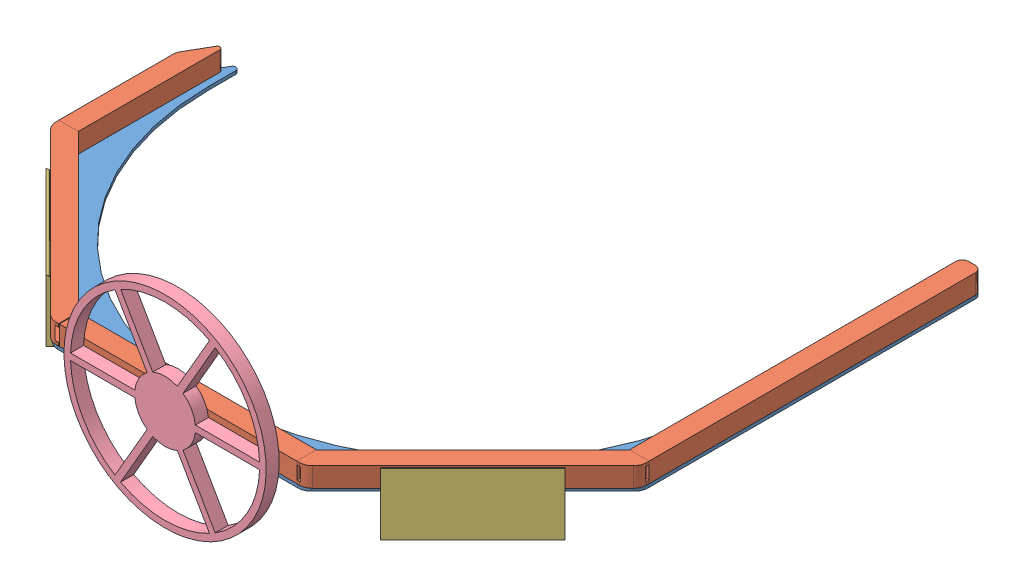
SolidWorks assembly recycling_rotate_weldment, configuration Default. Lengths in mm.
Overall size (582.57 228.04 508).
9 component instances, 4 part files, 24 mates.
Components (placement in the parent):
- recycling_rotate_plate-1: recycling_rotate_plate [Default] at origin size (574.68 3.17 495.3)
- recycling_rotate_tube-16: recycling_rotate_tube [-2] at (-115.2525 12.7 282.575) x (0 0 -1) z (1 0 0) size (19.05 19.05 231.14)
- recycling_rotate_tube-1: recycling_rotate_tube [Default] at (277.8125 12.7 120.65) x (-1 0 0) z (0 0 -1) size (19.05 19.05 323.85)
- recycling_rotate_tube-14: recycling_rotate_tube [-3] at (-277.8125 12.7 -463.55) size (19.05 19.05 140.36)
- recycling_rotate_tube-17: recycling_rotate_tube [-4] at (14.5071 12.7 387.9008) x (-0.707107 0 -0.707107) z (0.707107 0 -0.707107) size (19.05 19.05 242.47)
- recycling_rotate_tube-18: recycling_rotate_tube [-4] at (-14.5071 12.7 387.9008) x (0.707107 0 -0.707107) z (-0.707107 0 -0.707107) size (19.05 19.05 242.47)
- recycling_rotate_l-angle-1: recycling_rotate_l-angle [PreviewCfg] at (207.8029 -38.1 212.5654) x (-0.707107 0 -0.707107) z (0.707107 0 -0.707107) size (34.92 60.32 127)
- recycling_rotate_l-angle-2: recycling_rotate_l-angle [PreviewCfg] at (-207.8029 -38.1 212.5654) x (0.707107 0 -0.707107) z (0.707107 0 0.707107) size (34.92 60.32 127)
- recycling_rotate_wheel-1: recycling_rotate_wheel [Default] at (0.3175 12.7 292.1) x (0.984808 0.173648 0) z (0.173648 -0.984808 0) size (196.85 12.7 196.85)
Mates (geometry in assembly coordinates):
- Coincident1: coincident anti-aligned: plane of recycling_rotate_plate-1 through (0 3.175 0) normal (0 1 0); plane of recycling_rotate_tube-1 through (268.2875 3.175 -203.2) normal (0 -1 0)
- Coincident3: coincident aligned: plane of recycling_rotate_plate-1 through (287.3375 3.175 292.1) normal (1 0 0); plane of recycling_rotate_tube-1 through (287.3375 3.175 -203.2) normal (1 0 0)
- Coincident4: coincident anti-aligned: plane of recycling_rotate_plate-1 through (0 3.175 0) normal (0 1 0); plane of recycling_rotate_tube-14 through (-268.2875 3.175 120.65) normal (0 -1 0)
- Coincident6: coincident aligned: plane of recycling_rotate_plate-1 through (-287.3375 3.175 5.8941) normal (-1 0 0); plane of recycling_rotate_tube-14 through (-287.3375 3.175 120.65) normal (-1 0 0)
- Coincident7: coincident anti-aligned: plane of recycling_rotate_plate-1 through (0 3.175 0) normal (0 1 0); plane of recycling_rotate_tube-16 through (115.8875 3.175 273.05) normal (0 -1 0)
- Coincident13: coincident aligned: plane of recycling_rotate_plate-1 through (287.3375 3.175 292.1) normal (0 0 1); plane of recycling_rotate_tube-16 through (115.8875 3.175 292.1) normal (0 0 1)
- Coincident29: coincident anti-aligned: plane of recycling_rotate_plate-1 through (0 3.175 0) normal (0 1 0); plane of recycling_rotate_tube-17 through (414.1285 3.175 -25.191) normal (0 -1 0)
- Coincident33: coincident aligned: plane of recycling_rotate_tube-1 through (287.3375 3.175 -203.2) normal (1 0 0); plane of recycling_rotate_tube-17 through (287.3375 3.175 128.5408) normal (1 0 0)
- Coincident34: coincident aligned: plane of recycling_rotate_tube-16 through (115.8875 3.175 292.1) normal (0 0 1); plane of recycling_rotate_tube-17 through (123.7783 3.175 292.1) normal (0 0 1)
- Coincident35: coincident anti-aligned: plane of recycling_rotate_plate-1 through (0 3.175 0) normal (0 1 0); plane of recycling_rotate_tube-18 through (-414.1285 3.175 -25.191) normal (0 -1 0)
- Coincident36: coincident aligned: plane of recycling_rotate_tube-14 through (-287.3375 3.175 120.65) normal (-1 0 0); plane of recycling_rotate_tube-18 through (-287.3375 22.225 128.5408) normal (-1 0 0)
- Coincident37: coincident aligned: plane of recycling_rotate_tube-16 through (115.8875 3.175 292.1) normal (0 0 1); plane of recycling_rotate_tube-18 through (-123.7783 22.225 292.1) normal (0 0 1)
- Coincident38: coincident anti-aligned: plane of recycling_rotate_tube-1 through (277.8125 12.7 120.65) normal (0 0 1); plane of recycling_rotate_tube-17 through (14.5071 3.175 120.65) normal (0 0 -1)
- Coincident39: coincident anti-aligned: plane of recycling_rotate_tube-14 through (-277.8125 12.7 120.65) normal (0 0 1); plane of recycling_rotate_tube-18 through (-14.5071 22.225 120.65) normal (0 0 -1)
- Coincident40: coincident anti-aligned: plane of recycling_rotate_tube-16 through (115.8875 12.7 282.575) normal (1 0 0); plane of recycling_rotate_tube-17 through (115.8875 3.175 299.9908) normal (-1 0 0)
- Coincident41: coincident anti-aligned: plane of recycling_rotate_tube-17 through (427.5989 3.175 -11.7206) normal (0.707107 0 0.707107); plane of recycling_rotate_l-angle-1 through (250.4592 19.0551 165.4191) normal (-0.707107 0 -0.707107)
- Coincident42: coincident: plane of recycling_rotate_tube-17 through (414.1285 22.225 -25.191) normal (0 1 0); line of recycling_rotate_l-angle-1 through (252.7042 22.225 167.6642) axis (-0.707107 0 0.707107)
- Coincident43: coincident aligned: plane of recycling_rotate_l-angle-1 through (207.8029 -38.1 212.5654) normal (0.707107 0 -0.707107); plane of recycling_rotate_tube-17 through (198.8227 12.7 203.5852) normal (0.707107 0 -0.707107)
- Coincident44: coincident anti-aligned: plane of recycling_rotate_tube-18 through (-427.5989 22.225 -11.7206) normal (-0.707107 0 0.707107); plane of recycling_rotate_l-angle-2 through (-160.6566 19.0551 255.2217) normal (0.707107 0 -0.707107)
- Coincident45: coincident: plane of recycling_rotate_tube-18 through (-414.1285 22.225 -25.191) normal (0 1 0); line of recycling_rotate_l-angle-2 through (-162.9017 22.225 257.4667) axis (-0.707107 0 -0.707107)
- Coincident46: coincident anti-aligned: plane of recycling_rotate_tube-18 through (-198.8227 12.7 203.5852) normal (-0.707107 0 -0.707107); plane of recycling_rotate_l-angle-2 through (-207.8029 -38.1 212.5654) normal (0.707107 0 0.707107)
- Coincident50: coincident anti-aligned: plane of recycling_rotate_tube-16 through (115.8875 3.175 292.1) normal (0 0 1); plane of recycling_rotate_wheel-1 through (0.3175 12.7 292.1) normal (0 0 -1)
- Distance1: distance = 6.35 mm aligned: plane of recycling_rotate_wheel-1 through (-29.1651 15.875 292.1) normal (0 1 0); plane of recycling_rotate_tube-16 through (115.8875 22.225 273.05) normal (0 1 0)
- Coincident52: coincident: plane of recycling_rotate_tube-16 through (0.3175 12.7 282.575) normal (-1 0 0); point of recycling_rotate_wheel-1
